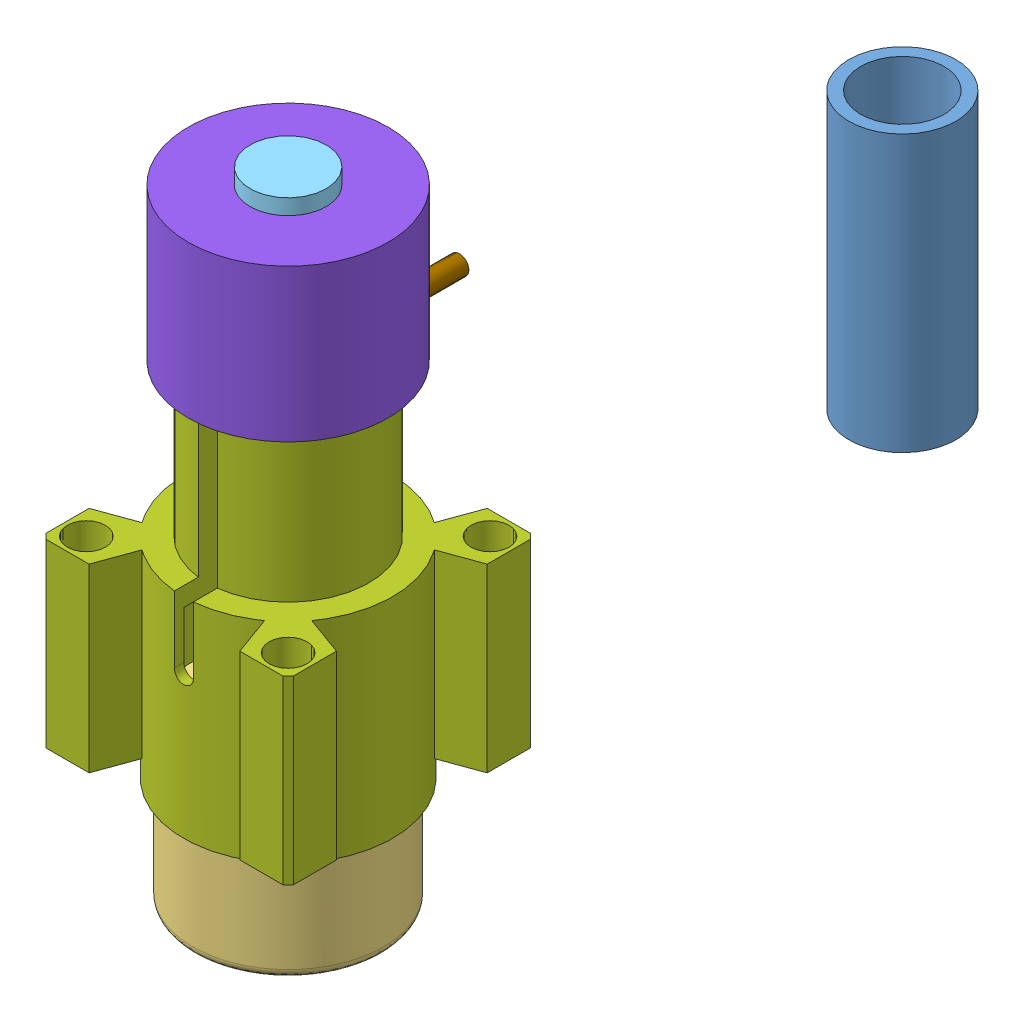
SolidWorks assembly Assemblage6, configuration Défaut. Lengths in mm.
Overall size (44.75 72.17 59.33).
11 component instances, 10 part files, 12 mates.
Components (placement in the parent):
- alésage porte bille-1: alésage porte bille [Défaut] at (-9.7526 -17.3328 0) (suppressed, hidden)
- ressort décompressé-1: ressort décompressé [Défaut] at (6.1507 31.1852 0) x (1 0 0) z (0 -1 0) size (11.25 11.25 29)
- ressort compressé-1: ressort compressé [Défaut] at (-18.8355 27.8924 39.5618) x (0.989109 0 0.147187) z (0 -1 0) size (11.25 11.25 11)
- Roulette à bille 687-679-modifiée-1: Roulette à bille 687-679-modifiée [Default] at (-13.8605 -30.0008 37.7318) x (0.694238 0 0.719745) z (-0.719745 0 0.694238) size (20 32.17 20)
  - Roulette D20-1: Roulette D20 [Default] at (-2.1367 -5.4811 4.8512) size (20 27 20)
  - bille D12_5-1: bille D12_5 [Default] at (-2.1367 -2.2311 4.8512) x (0.951271 -0.300034 -0.071154) z (0.043636 -0.097448 0.994284) size (12.5 12.5 12.5)
- tige filetée M8-1: tige filetée M8 [Défaut] at (-18.8355 -18.4818 39.5618) x (0.899142 0 -0.437656) z (0.437656 0 0.899142) size (8 50 8)
- bague de compression-1: bague de compression [Défaut] at (-18.8355 16.8924 39.5618) x (0 0 1) z (0 -1 0) size (13 13 5)
- alésage porte bille-2: alésage porte bille [Défaut] at (-18.8355 -21.1076 39.5618) size (26 44 26)
- Ecrou réglage hauteur-1: Ecrou réglage hauteur [Défaut] at (-18.8355 32.8924 39.5618) size (21 16 21)
- axe antirotation-1: axe antirotation [Défaut] at (-18.8355 13.6179 21.5618) x (0.85764 0.514251 0) z (0.514251 -0.85764 0) size (2 14 2)
Mates (geometry in assembly coordinates):
- Coaxiale1: concentric aligned: cylinder of Roulette à bille 687-679-modifiée-1/Roulette D20-1; cylinder of tige filetée M8-1
- Coïncidente1: coincident anti-aligned: plane of Roulette à bille 687-679-modifiée-1/Roulette D20-1 through (-18.8355 -18.4818 39.5618) normal (0 1 0); plane of tige filetée M8-1 through (-16.5876 -18.4818 38.4677) normal (0 -1 0)
- Coaxiale2: concentric anti-aligned: cylinder of tige filetée M8-1; cylinder of bague de compression-1
- Coaxiale3: concentric aligned: cylinder of Roulette à bille 687-679-modifiée-1/Roulette D20-1; cylinder of alésage porte bille-2
- Coaxiale4: concentric anti-aligned: cylinder of ressort compressé-1; cylinder of tige filetée M8-1
- Coïncidente6: coincident anti-aligned: plane of ressort compressé-1 through (-18.8355 16.8924 39.5618) normal (0 -1 0); plane of bague de compression-1 through (-18.8355 16.8924 39.5618) normal (0 1 0)
- Coaxiale5: concentric anti-aligned: cylinder of tige filetée M8-1; cylinder of Ecrou réglage hauteur-1
- Coïncidente7: coincident anti-aligned: plane of ressort compressé-1 through (-18.8355 27.8924 39.5618) normal (0 1 0); plane of Ecrou réglage hauteur-1 through (-27.3355 27.8924 39.5618) normal (0 -1 0)
- Distance1: distance = 8 mm anti-aligned: plane of Ecrou réglage hauteur-1 through (-27.3355 27.8924 39.5618) normal (0 -1 0); plane of alésage porte bille-2 through (-27.3355 19.8924 39.5618) normal (0 1 0)
- Coaxiale6: concentric anti-aligned: cylinder of bague de compression-1; cylinder of axe antirotation-1
- Tangent1: tangent anti-aligned: plane of axe antirotation-1 through (-18.8355 13.6179 35.5618) normal (0 0 1); cylinder of bague de compression-1
- Tangent4: tangent anti-aligned: cylinder of axe antirotation-1; plane of alésage porte bille-2 through (-17.8355 -9.1076 26.5618) normal (-1 0 0)
